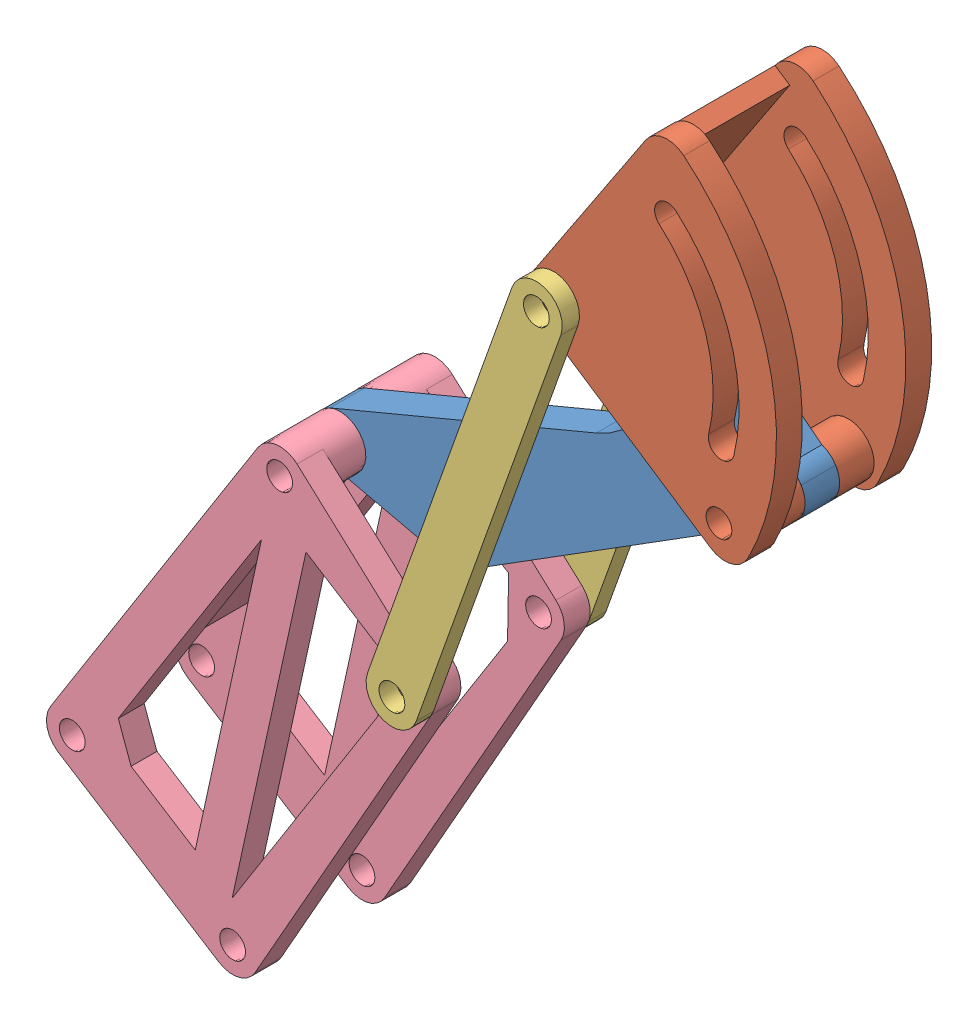
SolidWorks assembly assembly, configuration Default. Lengths in mm.
Overall size (97.15 111.4 22).
5 component instances, 4 part files, 10 mates.
Components (placement in the parent):
- [F1]ProximalPhalange-1: [F1]ProximalPhalange [Default] at (-2.4835 -4.9748 -0.4592) x (0.84704 0.531528 0) z (0 0 1) size (60.17 20 4)
- [F1]DistalPhalange_Joint-1: [F1]DistalPhalange_Joint [Default] at (11.4723 33.8281 -7.4592) x (0.552506 0.833509 0) z (0 0 1) size (29.83 29.83 18)
- [F1]MedialPhalange_Lever-1: [F1]MedialPhalange_Lever [Default] at (7.2551 11.1157 -9.4592) x (0.335009 0.942215 0) z (0 0 1) size (56 6 2)
- [F1]MedialPhalange-1: [F1]MedialPhalange [Default] at (-40.1872 -36.8079 -7.4592) x (0.534366 0.845253 0) z (0 0 1) size (51 28 18)
- [F1]MedialPhalange_Lever-2: [F1]MedialPhalange_Lever [Default] at (7.2551 11.1157 10.5408) x (0.335009 0.942215 0) z (0 0 1) size (56 6 2)
Mates (geometry in assembly coordinates):
- Concentric3: concentric: cylinder of [F1]DistalPhalange_Joint-1 through (15.6303 34.6711 -4.4592) axis (0 0 -1) radius 1.5; cylinder of [F1]MedialPhalange_Lever-1 through (15.6303 34.6711 -7.4592) axis (0 0 -1) radius 1.5
- Concentric6: concentric: cylinder of [F1]MedialPhalange_Lever-1 through (-1.1201 -12.4396 -7.4592) axis (0 0 -1) radius 1.5; cylinder of [F1]MedialPhalange-1 through (-1.1201 -12.4396 -4.4592) axis (0 0 -1) radius 1.5
- Coincident2: coincident: plane of [F1]DistalPhalange_Joint-1 through (11.4723 33.8281 -7.4592) normal (0 0 -1); plane of [F1]MedialPhalange-1 through (-1.1201 -12.4396 -7.4592) normal (0 0 -1)
- Coincident3: coincident: plane of [F1]MedialPhalange_Lever-1 through (-1.1201 -12.4396 -7.4592) normal (0 0 1); plane of [F1]MedialPhalange-1 through (-1.1201 -12.4396 -7.4592) normal (0 0 -1)
- Concentric8: concentric: circle of [F1]DistalPhalange_Joint-1; circle of [F1]MedialPhalange_Lever-2
- Angle1: planar angle = 0 rad: plane of [F1]MedialPhalange_Lever-1 through (-3.9468 -11.4346 -7.4592) normal (-0.942215 0.335009 0); plane of [F1]MedialPhalange_Lever-2 through (-3.9468 -11.4346 12.5408) normal (-0.942215 0.335009 0)
- Concentric10: concentric: circle of [F1]ProximalPhalange-1; cylinder of [F1]DistalPhalange_Joint-1 through (34.801 21.9635 10.5408) axis (0 0 -1) radius 1.5
- Coincident7: coincident: plane of [F1]ProximalPhalange-1 through (-16.1407 1.2285 3.5408) normal (0 0 1); circle of [F1]DistalPhalange_Joint-1
- Concentric11: concentric: cylinder of [F1]ProximalPhalange-1 through (-16.1407 1.2285 3.5408) axis (0 0 -1) radius 1.5; circle of [F1]MedialPhalange-1
- Coincident14: coincident: plane of [F1]DistalPhalange_Joint-1 through (11.4723 33.8281 10.5408) normal (0 0 1); plane of [F1]MedialPhalange_Lever-2 through (-1.1201 -12.4396 10.5408) normal (0 0 -1)
